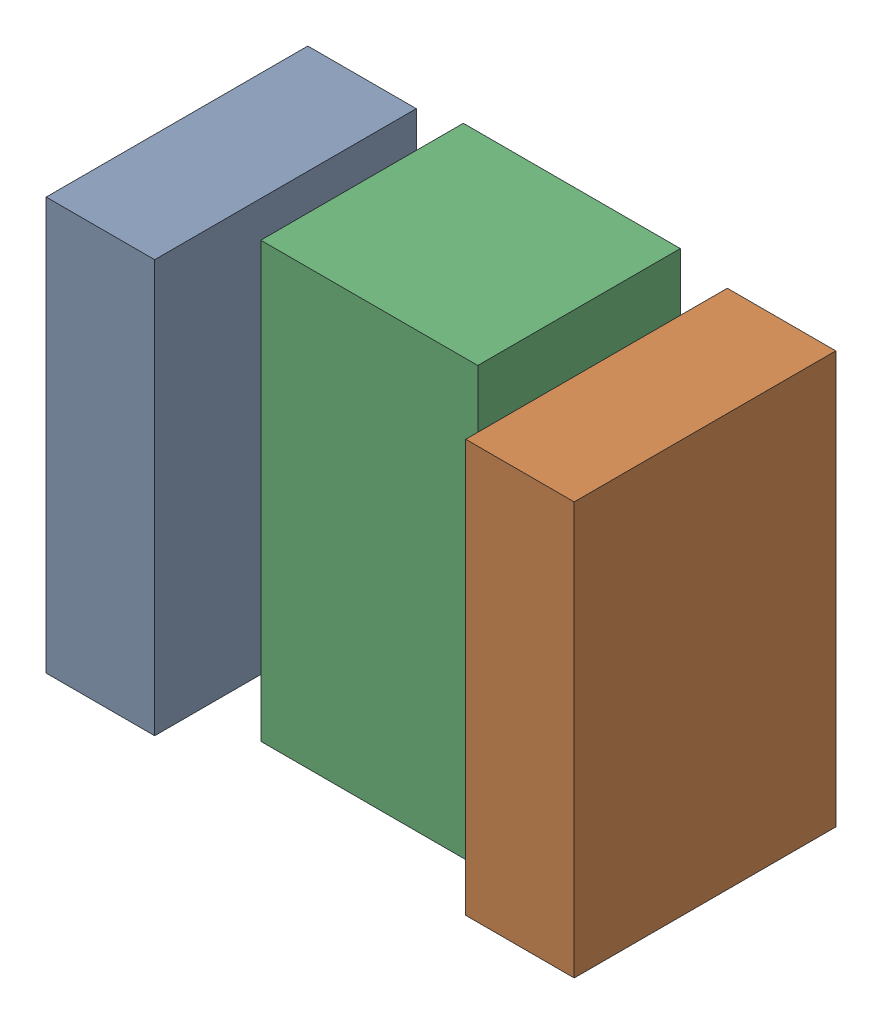
SolidWorks assembly C7_Motor_9Kanaloa_v2.0.0_Motor, configuration Default. Lengths in mm.
Overall size (3.65 3 1.81).
6 component instances, 2 part files, 0 mates.
Components (placement in the parent):
- 334788400-1: 334788400 [Default] at (59.467 167.386 0) size (0.75 2.85 1.81)
  - Extruded_5-1: Extruded_5 [Default] at origin size (0.75 2.85 1.81)
- 334788400-2: 334788400 [Default] at (62.367 167.386 0) size (0.75 2.85 1.81)
  - Extruded_5-1: Extruded_5 [Default] at origin size (0.75 2.85 1.81)
- 334788656-1: 334788656 [Default] at (60.917 167.386 0) size (1.5 3 1.4)
  - Extruded_1-1: Extruded_1 [Default] at origin size (1.5 3 1.4)
